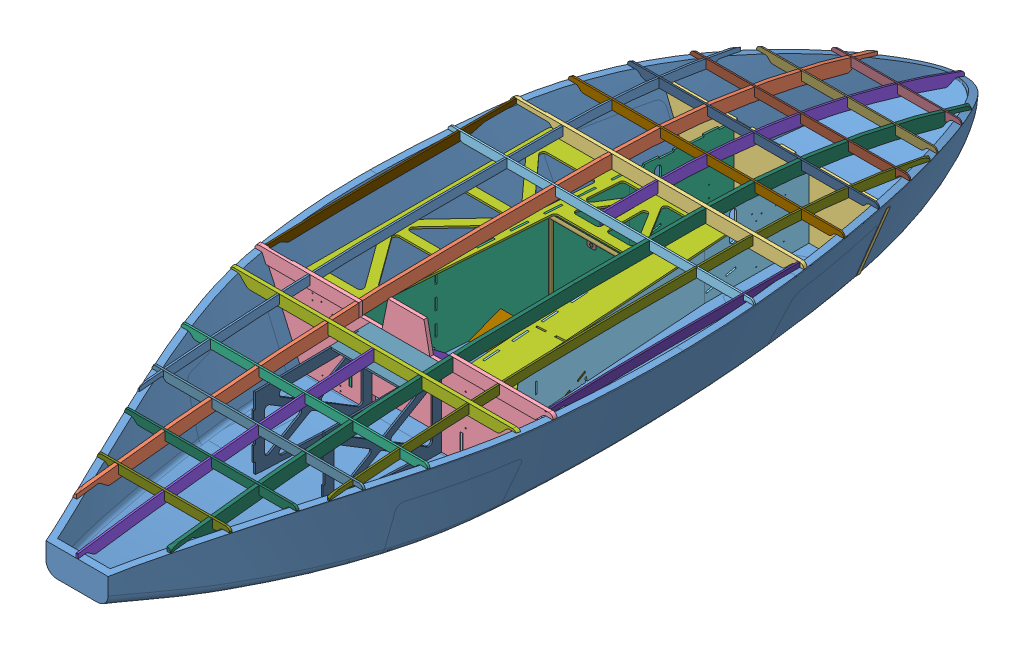
SolidWorks assembly ArrayRibsASSY, configuration Default. Lengths in mm.
Overall size (2230.46 796.8 5158.73).
40 component instances, 37 part files, 5 mates.
Components (placement in the parent):
- V4 Bottom Mold Array Layup-1: V4 Bottom Mold Array Layup [Default] at (-1494.4165 -2964.8597 -4078.9205) size (2230.46 796.8 5158.73)
- Interior Frame-1: Interior Frame [Default] at (802.1076 -1700.8679 1799.1854) x (-1 0 0) z (0 0 -1) size (1636.82 634.69 2739.24)
  - Floor Panel-1: Floor Panel [Default] at (835.5965 1316.5356 1074.9175) x (1 0 0) z (0 -1 0) size (939.76 2072.64 10.16)
  - Front Bulkhead-1: Front Bulkhead [Default] at (162.873 1776.2756 3127.2375) size (1308.56 425.46 20.32)
  - Rearward Bulkhead-1: Rearward Bulkhead [Default] at (876.0943 1625.7899 1074.9175) size (1636.82 634.69 21.09)
  - Part11-1: Part11 [Default] at (835.5965 1306.3756 1074.9175) x (1 0 0) z (0 -1 0) size (111.78 2072.64 469.9)
  - MirrorPart11-2: MirrorPart11 [Default] at (835.5965 1306.3756 1074.9175) x (-1 0 0) z (0 1 0) size (111.78 2072.64 469.9)
  - Part12-1: Part12 [Default] at (835.5965 1766.1156 1074.9175) x (-1 0 0) z (0 1 0) size (1244.67 1463.04 10.16)
  - Part13-1: Part13 [Default] at origin
  - Part14-1: Part14 [Default] at (835.5965 0 0) x (0 0 -1) z (1 0 0) size (510.84 377.19 622.87)
  - Part15-1: Part15 [Default] at (835.5965 0 0) x (0 0 -1) z (1 0 0) size (234.38 107.63 550.98)
  - Battery Side Holder-1: Battery Side Holder [Default] at (634.9365 1306.3669 1095.2375) x (0 0 -1) z (1 0 0) size (686.5 466.26 10.16)
  - Battery Side Holder-2: Battery Side Holder [Default] at (1026.0965 1306.3707 1095.2375) x (0 0 -1) z (1 0 0) size (686.5 466.26 10.16)
  - Battery Tray-1: Battery Tray [Default] at (634.9365 1306.3843 1074.4968) x (1 0 0) z (0 -0.041404 0.999142) size (401.32 10.16 666.75)
  - Part5^Interior Frame-1: Part5^Interior Frame [Default] at (0 0 2118.8575) size (473.12 449.58 19.05) (virtual)
  - Part6^Interior Frame-1: Part6^Interior Frame [Default] at (0 0 2118.8575) size (50.8 31.75 1.65) (virtual)
  - Part1^Interior Frame-1: Part1^Interior Frame [Default] at (1026.0965 1783.5631 1515.4068) x (0 -0.013523 -0.999909) z (0 0.999909 -0.013523) size (228.6 401.32 10.16) (virtual)
- Array Layout-1: Array Layout [Default] at (-3467.9225 -5242.9278 -8295.8481) size (2244.1 893.61 5149.59)
  - Array Frame V2-1: Array Frame V2 [Default] at (1973.5044 2278.0681 4216.9276) size (2244.1 893.61 5149.59) (hidden)
  - Part2^Array Layout-1: Part2^Array Layout [Default] at (1973.5044 5406.8754 4216.9276) x (-1 0 0) z (0 -1 0) size (22.93 4512.12 270.66) (virtual)
  - Part3^Array Layout-2: Part3^Array Layout [Default] at (0 5025.8754 0) x (-1 0 0) z (0 -1 0) size (12.76 3392.86 137.81) (virtual)
  - Part4^Array Layout-1: Part4^Array Layout [Default] at (0 5025.8754 0) x (-1 0 0) z (0 -1 0) size (10.16 1424.94 59.48) (virtual)
  - MirrorPart4^Array Layout-3: MirrorPart4^Array Layout [Default] at (6868.864 5025.8754 0) x (1 0 0) z (0 1 0) size (10.16 1424.94 59.48) (virtual)
  - MirrorPart3^Array Layout-4: MirrorPart3^Array Layout [Default] at (6868.864 5025.8754 0) x (1 0 0) z (0 1 0) size (12.76 3392.86 137.81) (virtual)
  - MirrorPart2^Array Layout-3: MirrorPart2^Array Layout [Default] at (4895.3596 5406.8754 4216.9276) x (1 0 0) z (0 1 0) size (22.93 4512.12 270.66) (virtual)
  - Part9^Array Layout-1: Part9^Array Layout [Default] at (0 5025.8754 0) x (-1 0 0) z (0 -1 0) size (1654.54 20.33 77.9) (virtual)
  - Part10^Array Layout-1: Part10^Array Layout [Default] at (0 5025.8754 0) x (-1 0 0) z (0 -1 0) size (1685.86 20.32 76.37) (virtual)
  - Part11^Array Layout-1: Part11^Array Layout [Default] at (0 5025.8754 0) x (-1 0 0) z (0 -1 0) size (1724.27 10.17 52.31) (virtual)
  - Part12^Array Layout-1: Part12^Array Layout [Default] at (0 5025.8754 0) x (-1 0 0) z (0 -1 0) size (1397.96 10.16 52.43) (virtual)
  - Part5^Array Layout-1: Part5^Array Layout [Default] at (0 5025.8754 0) x (-1 0 0) z (0 -1 0) size (1623.76 20.32 66) (virtual)
  - Part1^Array Layout-1: Part1^Array Layout [Default] at (0 5025.8754 0) x (-1 0 0) z (0 -1 0) size (10.55 4993.42 381) (virtual)
  - Part6^Array Layout-1: Part6^Array Layout [Default] at (0 5025.8754 0) x (-1 0 0) z (0 -1 0) size (1553.22 10.16 52.29) (virtual)
  - Part7^Array Layout-1: Part7^Array Layout [Default] at (0 5025.8754 0) x (-1 0 0) z (0 -1 0) size (1416.69 10.24 52.35) (virtual)
  - Part8^Array Layout-1: Part8^Array Layout [Default] at (0 5025.8754 0) x (-1 0 0) z (0 -1 0) size (1239.18 10.16 52.42) (virtual)
  - Part13^Array Layout-1: Part13^Array Layout [Default] at (0 5025.8754 0) x (-1 0 0) z (0 -1 0) size (1018.77 10.16 254.55) (virtual)
  - Part14^Array Layout-1: Part14^Array Layout [Default] at origin size (734.38 52.67 10.16) (virtual)
  - Part15^Array Layout-1: Part15^Array Layout [Default] at (0 5025.8754 0) x (-1 0 0) z (0 -1 0) size (1198 10.16 316.03) (virtual)
  - Part16^Array Layout-1: Part16^Array Layout [Default] at (0 5025.8754 0) x (-1 0 0) z (0 -1 0) size (979.81 10.16 52.52) (virtual)
  - Part17^Array Layout-1: Part17^Array Layout [Default] at (0 5025.8754 0) x (-1 0 0) z (0 -1 0) size (754.82 10.16 52.51) (virtual)
- Part1^ArrayRibsASSY-1: Part1^ArrayRibsASSY [Default] at origin (virtual)
Mates (geometry in assembly coordinates):
- Coincident1: coincident aligned: plane of V4 Bottom Mold Array Layup-1 through (-650.4389 -394.4924 32.3058) normal (0 -1 0); plane of Interior Frame-1/Floor Panel-1 through (-33.4889 -394.4924 724.2679) normal (0 -1 0)
- Coincident2: coincident anti-aligned: line of V4 Bottom Mold Array Layup-1 through (-488.8829 -394.4924 -1348.3721) axis (1 0 0); line of Interior Frame-1/Front Bulkhead-1 through (-74.6246 -394.4924 -1348.3721) axis (-1 0 0)
- Coincident3: coincident: point of Interior Frame-1/Floor Panel-1; unknown of V4 Bottom Mold Array Layup-1
- Coincident4: coincident: unknown of V4 Bottom Mold Array Layup-1; unknown of Array Layout-1/Array Frame V2-1
- Concentric1: concentric aligned: cylinder of V4 Bottom Mold Array Layup-1 through (-1494.4165 -16889.6757 44.8279) axis (1 0 0) radius 17028.5833; cylinder of Array Layout-1/Array Frame V2-1 through (-1494.4181 -16889.6757 44.8279) axis (1 0 0) radius 17028.5833
